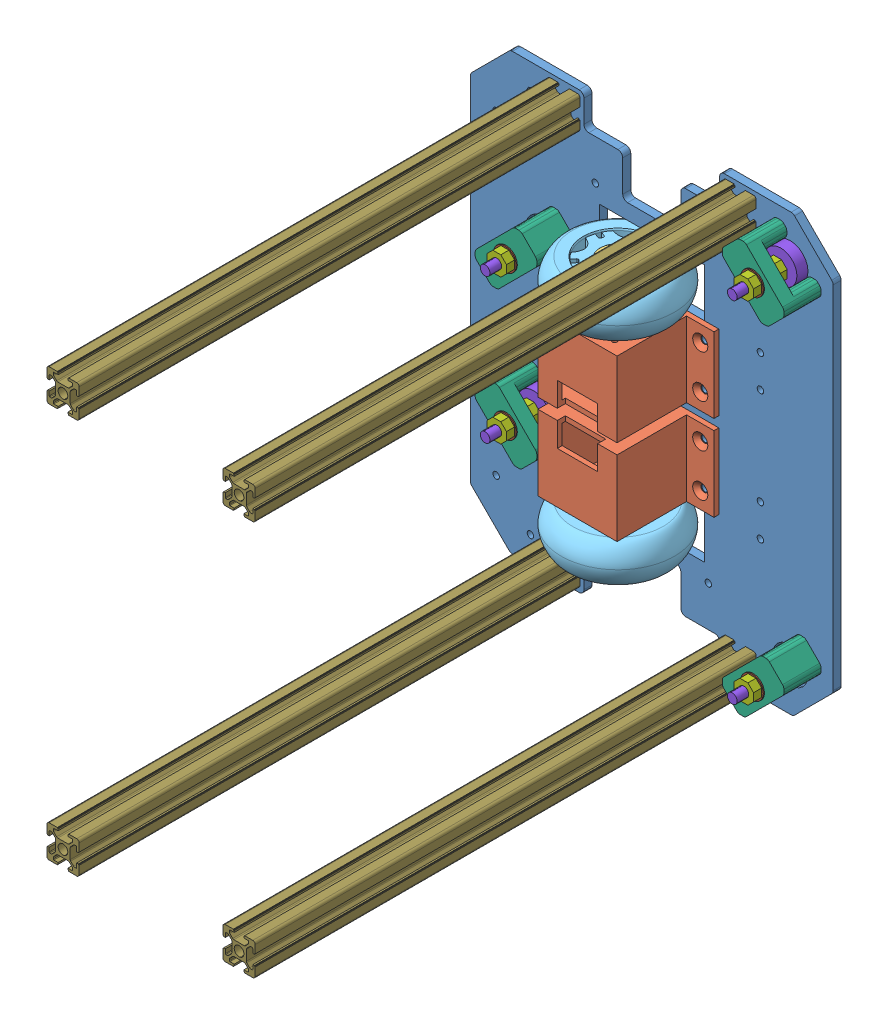
SolidWorks assembly base roulante, configuration Défaut. Lengths in mm.
Overall size (224.5 269.5 367.12).
63 component instances, 12 part files, 32 mates.
Components (placement in the parent):
- plaque base roulante 2-1: plaque base roulante 2 [Défaut] at (315.8571 -54.1365 122.0217) size (224.5 269.5 5)
- support-1: support [Défaut] at (206.8571 77.3635 170.0217) x (-1 0 0) z (0 -1 0) size (83 46 46.5)
- support-2: support [Défaut] at (249.8571 83.861 170.0217) x (1 0 0) z (0 1 0) size (83 46 46.5)
- Assemblage 5mm-1: Assemblage 5mm [Défaut] at (210.2333 168.7277 150.2073) x (0.837948 0 -0.54575) z (0 -1 0) size (70.03 70.03 25.12)
  - moyeu pololu (axe 5mm) part 2-1: moyeu pololu (axe 5mm) part 2 [Défaut] at (16.3796 8.0597 10.6516) size (21.9 21.9 3)
  - moyeux pololu (axe 5mm)-1: moyeux pololu (axe 5mm) [Défaut] at (16.3796 8.0597 27.1516) x (0.866025 0.5 0) z (0 0 1) size (22 22 12)
  - Roue Scooter noire 70x25 mm 3272-1: Roue Scooter noire 70x25 mm 3272 [Défaut] at (16.3796 8.0597 22.1516) size (70.03 70.03 25.12)
- Assemblage 5mm-2: Assemblage 5mm [Défaut] at (224.692 -6.3904 165.9052) x (0.612655 0 -0.79035) z (0 1 0) size (70.03 70.03 25.12)
  - moyeu pololu (axe 5mm) part 2-1: moyeu pololu (axe 5mm) part 2 [Défaut] at (16.3796 8.0597 10.6516) size (21.9 21.9 3)
  - moyeux pololu (axe 5mm)-1: moyeux pololu (axe 5mm) [Défaut] at (16.3796 8.0597 27.1516) x (0.866025 0.5 0) z (0 0 1) size (22 22 12)
  - Roue Scooter noire 70x25 mm 3272-1: Roue Scooter noire 70x25 mm 3272 [Défaut] at (16.3796 8.0597 22.1516) size (70.03 70.03 25.12)
- Assemblage Roue Porteuse-1: Assemblage Roue Porteuse [Défaut] at (293.5978 171.1781 157.1111) x (0.707107 -0.707107 0) z (-0.707107 -0.707107 0) size (40 50.71 20)
  - Support Bille porteuse-1: Support Bille porteuse [Défaut] at (1.9744 -30.0894 -26.9817) size (40 23 20)
  - Ecrou M6-3: Ecrou M6 [Défaut] at (1.9744 -17.1894 -26.9817) x (1 0 0) z (0 -1 0) size (12 12 5)
  - Ecrou M6-2: Ecrou M6 [Défaut] at (1.9744 -1.3894 -26.9817) x (1 0 0) z (0 -1 0) size (12 12 5)
  - Bille porteuse ALWAYE D12_7-2: Bille porteuse ALWAYE D12_7 [Défaut] at (1.9744 -30.1894 -26.9817) size (20 46.5 20)
  - Bille D12-2: Bille D12 [Défaut] at (1.9744 -38.8998 -26.9817) size (12 12 12)
  - Insert M4-2: Insert M4 [Défaut] at (16.9744 -30.0894 -26.9817) x (-0.837169 0 -0.546944) z (0 1 0) size (7 7 8)
  - Insert M4-3: Insert M4 [Défaut] at (-13.0256 -30.0894 -26.9817) x (-0.837169 0 -0.546944) z (0 1 0) size (7 7 8)
  - Rondelle M6-6: Rondelle M6 [Défaut] at (1.9744 -17.1894 -26.9817) x (1 0 0) z (0 1 0) size (14 14 0.7)
  - Rondelle M6-7: Rondelle M6 [Défaut] at (1.9744 -16.4894 -26.9817) x (1 0 0) z (0 1 0) size (14 14 0.7)
  - Rondelle M6-5: Rondelle M6 [Défaut] at (1.9744 -15.7894 -26.9817) x (1 0 0) z (0 1 0) size (14 14 0.7)
  - Rondelle M6-4: Rondelle M6 [Défaut] at (1.9744 -7.0894 -26.9817) x (1 0 0) z (0 1 0) size (14 14 0.7)
- Assemblage Roue Porteuse-2: Assemblage Roue Porteuse [Défaut] at (331.7557 -48.1115 157.1111) x (0.707107 0.707107 0) z (0.707107 -0.707107 0) size (40 50.71 20)
  - Support Bille porteuse-1: Support Bille porteuse [Défaut] at (1.9744 -30.0894 -26.9817) size (40 23 20)
  - Ecrou M6-3: Ecrou M6 [Défaut] at (1.9744 -17.1894 -26.9817) x (1 0 0) z (0 -1 0) size (12 12 5)
  - Ecrou M6-2: Ecrou M6 [Défaut] at (1.9744 -1.3894 -26.9817) x (1 0 0) z (0 -1 0) size (12 12 5)
  - Bille porteuse ALWAYE D12_7-2: Bille porteuse ALWAYE D12_7 [Défaut] at (1.9744 -30.1894 -26.9817) size (20 46.5 20)
  - Bille D12-2: Bille D12 [Défaut] at (1.9744 -38.8998 -26.9817) size (12 12 12)
  - Insert M4-2: Insert M4 [Défaut] at (16.9744 -30.0894 -26.9817) x (-0.837169 0 -0.546944) z (0 1 0) size (7 7 8)
  - Insert M4-3: Insert M4 [Défaut] at (-13.0256 -30.0894 -26.9817) x (-0.837169 0 -0.546944) z (0 1 0) size (7 7 8)
  - Rondelle M6-6: Rondelle M6 [Défaut] at (1.9744 -17.1894 -26.9817) x (1 0 0) z (0 1 0) size (14 14 0.7)
  - Rondelle M6-7: Rondelle M6 [Défaut] at (1.9744 -16.4894 -26.9817) x (1 0 0) z (0 1 0) size (14 14 0.7)
  - Rondelle M6-5: Rondelle M6 [Défaut] at (1.9744 -15.7894 -26.9817) x (1 0 0) z (0 1 0) size (14 14 0.7)
  - Rondelle M6-4: Rondelle M6 [Défaut] at (1.9744 -7.0894 -26.9817) x (1 0 0) z (0 1 0) size (14 14 0.7)
- Assemblage Roue Porteuse-3: Assemblage Roue Porteuse [Défaut] at (178.7912 104.8859 157.1111) x (0.707107 0.707107 0) z (0.707107 -0.707107 0) size (40 50.71 20)
  - Support Bille porteuse-1: Support Bille porteuse [Défaut] at (1.9744 -30.0894 -26.9817) size (40 23 20)
  - Ecrou M6-3: Ecrou M6 [Défaut] at (1.9744 -17.1894 -26.9817) x (1 0 0) z (0 -1 0) size (12 12 5)
  - Ecrou M6-2: Ecrou M6 [Défaut] at (1.9744 -1.3894 -26.9817) x (1 0 0) z (0 -1 0) size (12 12 5)
  - Bille porteuse ALWAYE D12_7-2: Bille porteuse ALWAYE D12_7 [Défaut] at (1.9744 -30.1894 -26.9817) size (20 46.5 20)
  - Bille D12-2: Bille D12 [Défaut] at (1.9744 -38.8998 -26.9817) size (12 12 12)
  - Insert M4-2: Insert M4 [Défaut] at (16.9744 -30.0894 -26.9817) x (-0.837169 0 -0.546944) z (0 1 0) size (7 7 8)
  - Insert M4-3: Insert M4 [Défaut] at (-13.0256 -30.0894 -26.9817) x (-0.837169 0 -0.546944) z (0 1 0) size (7 7 8)
  - Rondelle M6-6: Rondelle M6 [Défaut] at (1.9744 -17.1894 -26.9817) x (1 0 0) z (0 1 0) size (14 14 0.7)
  - Rondelle M6-7: Rondelle M6 [Défaut] at (1.9744 -16.4894 -26.9817) x (1 0 0) z (0 1 0) size (14 14 0.7)
  - Rondelle M6-5: Rondelle M6 [Défaut] at (1.9744 -15.7894 -26.9817) x (1 0 0) z (0 1 0) size (14 14 0.7)
  - Rondelle M6-4: Rondelle M6 [Défaut] at (1.9744 -7.0894 -26.9817) x (1 0 0) z (0 1 0) size (14 14 0.7)
- Assemblage Roue Porteuse-4: Assemblage Roue Porteuse [Défaut] at (181.5834 53.5463 157.1111) x (-0.707107 0.707107 0) z (0.707107 0.707107 0) size (40 50.71 20)
  - Support Bille porteuse-1: Support Bille porteuse [Défaut] at (1.9744 -30.0894 -26.9817) size (40 23 20)
  - Ecrou M6-3: Ecrou M6 [Défaut] at (1.9744 -17.1894 -26.9817) x (1 0 0) z (0 -1 0) size (12 12 5)
  - Ecrou M6-2: Ecrou M6 [Défaut] at (1.9744 -1.3894 -26.9817) x (1 0 0) z (0 -1 0) size (12 12 5)
  - Bille porteuse ALWAYE D12_7-2: Bille porteuse ALWAYE D12_7 [Défaut] at (1.9744 -30.1894 -26.9817) size (20 46.5 20)
  - Bille D12-2: Bille D12 [Défaut] at (1.9744 -38.8998 -26.9817) size (12 12 12)
  - Insert M4-2: Insert M4 [Défaut] at (16.9744 -30.0894 -26.9817) x (-0.837169 0 -0.546944) z (0 1 0) size (7 7 8)
  - Insert M4-3: Insert M4 [Défaut] at (-13.0256 -30.0894 -26.9817) x (-0.837169 0 -0.546944) z (0 1 0) size (7 7 8)
  - Rondelle M6-6: Rondelle M6 [Défaut] at (1.9744 -17.1894 -26.9817) x (1 0 0) z (0 1 0) size (14 14 0.7)
  - Rondelle M6-7: Rondelle M6 [Défaut] at (1.9744 -16.4894 -26.9817) x (1 0 0) z (0 1 0) size (14 14 0.7)
  - Rondelle M6-5: Rondelle M6 [Défaut] at (1.9744 -15.7894 -26.9817) x (1 0 0) z (0 1 0) size (14 14 0.7)
  - Rondelle M6-4: Rondelle M6 [Défaut] at (1.9744 -7.0894 -26.9817) x (1 0 0) z (0 1 0) size (14 14 0.7)
- Profilé Aluminium Bosch Rexroth 20 x 20 mm-1: Profilé Aluminium Bosch Rexroth 20 x 20 mm [Défaut] at (173.8571 202.861 127.0217) x (1 0 0) z (0 -1 0) size (20 339 20)
- Profilé Aluminium Bosch Rexroth 20 x 20 mm-2: Profilé Aluminium Bosch Rexroth 20 x 20 mm [Défaut] at (282.8571 -41.6365 127.0217) x (1 0 0) z (0 -1 0) size (20 339 20)
- Profilé Aluminium Bosch Rexroth 20 x 20 mm-3: Profilé Aluminium Bosch Rexroth 20 x 20 mm [Défaut] at (173.8571 -41.6365 127.0217) x (1 0 0) z (0 -1 0) size (20 339 20)
- Profilé Aluminium Bosch Rexroth 20 x 20 mm-4: Profilé Aluminium Bosch Rexroth 20 x 20 mm [Défaut] at (282.8571 202.861 127.0217) x (1 0 0) z (0 -1 0) size (20 339 20)
Mates (geometry in assembly coordinates):
- Coïncidente1: coincident anti-aligned: plane of plaque base roulante 2-1 through (315.8571 -54.1365 127.0217) normal (0 0 1); plane of support-1 through (249.8571 30.8635 127.0217) normal (0 0 -1)
- Coïncidente2: coincident anti-aligned: plane of plaque base roulante 2-1 through (315.8571 -54.1365 127.0217) normal (0 0 1); plane of support-2 through (206.8571 130.361 127.0217) normal (0 0 -1)
- Coïncidente3: coincident aligned: plane of plaque base roulante 2-1 through (260.8571 130.361 127.0217) normal (0 1 0); plane of support-2 through (249.8571 130.361 170.0217) normal (0 1 0)
- Coaxiale1: concentric aligned: cylinder of plaque base roulante 2-1 through (195.3571 120.361 122.0217) axis (0 0 1) radius 2; circle of support-2
- Parallèle1: parallel anti-aligned: plane of support-1 through (206.8571 77.3635 170.0217) normal (0 1 0); plane of support-2 through (249.8571 83.861 170.0217) normal (0 -1 0)
- Coaxiale2: concentric aligned: circle of plaque base roulante 2-1; circle of support-1
- Coaxiale3: concentric aligned: cylinder of plaque base roulante 2-1 through (261.3571 67.3635 122.0217) axis (0 0 1) radius 2; circle of support-1
- Coaxiale4: concentric anti-aligned: circle of support-1; circle of Assemblage 5mm-2/moyeux pololu (axe 5mm)-1
- Coaxiale5: concentric anti-aligned: circle of support-2; cylinder of Assemblage 5mm-1/moyeux pololu (axe 5mm)-1 through (228.3571 147.0761 148.0217) axis (0 -1 0) radius 2.51
- Coïncidente7: coincident anti-aligned: plane of plaque base roulante 2-1 through (315.8571 -54.1365 127.0217) normal (0 0 1); plane of Assemblage Roue Porteuse-1/Support Bille porteuse-1 through (314.0729 188.861 127.0217) normal (0 0 -1)
- Coaxiale6: concentric anti-aligned: cylinder of plaque base roulante 2-1 through (314.0729 188.861 122.0207) axis (0 0 1) radius 11; cylinder of Assemblage Roue Porteuse-1/Bille porteuse ALWAYE D12_7-2 through (314.0729 188.861 130.9217) axis (0 0 -1) radius 10
- Coaxiale7: concentric anti-aligned: circle of plaque base roulante 2-1; cylinder of Assemblage Roue Porteuse-1/Insert M4-2 through (324.6795 178.2544 135.0217) axis (0 0 -1) radius 2
- Coaxiale8: concentric anti-aligned: cylinder of plaque base roulante 2-1 through (314.0729 -27.6365 122.0207) axis (0 0 1) radius 11; cylinder of Assemblage Roue Porteuse-2/Bille porteuse ALWAYE D12_7-2 through (314.0729 -27.6365 130.9217) axis (0 0 -1) radius 10
- Coïncidente9: coincident anti-aligned: plane of plaque base roulante 2-1 through (315.8571 -54.1365 127.0217) normal (0 0 1); plane of Assemblage Roue Porteuse-2/Support Bille porteuse-1 through (314.0729 -27.6365 127.0217) normal (0 0 -1)
- Coaxiale9: concentric anti-aligned: cylinder of plaque base roulante 2-1 through (324.6795 -17.0299 122.0207) axis (0 0 1) radius 2; cylinder of Assemblage Roue Porteuse-2/Insert M4-2 through (324.6795 -17.0299 135.0217) axis (0 0 -1) radius 2
- Coaxiale10: concentric anti-aligned: cylinder of plaque base roulante 2-1 through (161.1084 35.8635 122.0207) axis (0 0 1) radius 11; cylinder of Assemblage Roue Porteuse-4/Bille porteuse ALWAYE D12_7-2 through (161.1084 35.8635 130.9217) axis (0 0 -1) radius 10
- Coïncidente10: coincident anti-aligned: plane of plaque base roulante 2-1 through (315.8571 -54.1365 127.0217) normal (0 0 1); plane of Assemblage Roue Porteuse-4/Support Bille porteuse-1 through (161.1084 35.8635 127.0217) normal (0 0 -1)
- Coaxiale11: concentric anti-aligned: cylinder of plaque base roulante 2-1 through (171.715 25.2569 122.0207) axis (0 0 1) radius 2; cylinder of Assemblage Roue Porteuse-4/Insert M4-3 through (171.715 25.2569 135.0217) axis (0 0 -1) radius 2
- Coaxiale13: concentric anti-aligned: circle of plaque base roulante 2-1; cylinder of Assemblage Roue Porteuse-3/Bille porteuse ALWAYE D12_7-2 through (161.1084 125.361 130.9217) axis (0 0 -1) radius 10
- Coïncidente12: coincident aligned: circle of plaque base roulante 2-1; circle of Assemblage Roue Porteuse-3/Insert M4-3
- Coïncidente13: coincident anti-aligned: plane of plaque base roulante 2-1 through (315.8571 -54.1365 127.0217) normal (0 0 1); plane of Profilé Aluminium Bosch Rexroth 20 x 20 mm-3 through (173.8571 -41.6365 127.0217) normal (0 0 -1)
- Coïncidente14: coincident anti-aligned: plane of plaque base roulante 2-1 through (315.8571 -54.1365 127.0217) normal (0 0 1); plane of Profilé Aluminium Bosch Rexroth 20 x 20 mm-2 through (282.8571 -41.6365 127.0217) normal (0 0 -1)
- Coïncidente15: coincident anti-aligned: plane of plaque base roulante 2-1 through (315.8571 -54.1365 127.0217) normal (0 0 1); plane of Profilé Aluminium Bosch Rexroth 20 x 20 mm-4 through (282.8571 202.861 127.0217) normal (0 0 -1)
- Coïncidente16: coincident anti-aligned: plane of plaque base roulante 2-1 through (315.8571 -54.1365 127.0217) normal (0 0 1); plane of Profilé Aluminium Bosch Rexroth 20 x 20 mm-1 through (173.8571 202.861 127.0217) normal (0 0 -1)
- Coaxiale14: concentric anti-aligned: cylinder of plaque base roulante 2-1 through (173.8571 -41.6365 122.0207) axis (0 0 1) radius 3; cylinder of Profilé Aluminium Bosch Rexroth 20 x 20 mm-3 through (173.8571 -41.6365 466.0217) axis (0 0 -1) radius 3
- Coaxiale15: concentric anti-aligned: cylinder of plaque base roulante 2-1 through (282.8571 -41.6365 122.0207) axis (0 0 1) radius 3; cylinder of Profilé Aluminium Bosch Rexroth 20 x 20 mm-2 through (282.8571 -41.6365 466.0217) axis (0 0 -1) radius 3
- Coïncidente17: coincident anti-aligned: cylinder of plaque base roulante 2-1 through (282.8571 202.861 122.0207) axis (0 0 1) radius 3; circle of Profilé Aluminium Bosch Rexroth 20 x 20 mm-4
- Coïncidente18: coincident anti-aligned: circle of plaque base roulante 2-1; cylinder of Profilé Aluminium Bosch Rexroth 20 x 20 mm-1 through (173.8571 202.861 466.0217) axis (0 0 -1) radius 3
- Parallèle2: parallel aligned: plane of plaque base roulante 2-1 through (140.8571 215.361 127.0217) normal (0 1 0); plane of Profilé Aluminium Bosch Rexroth 20 x 20 mm-1 through (163.8571 212.861 466.0217) normal (0 1 0)
- Parallèle3: parallel aligned: plane of plaque base roulante 2-1 through (140.8571 215.361 127.0217) normal (0 1 0); plane of Profilé Aluminium Bosch Rexroth 20 x 20 mm-4 through (272.8571 212.861 466.0217) normal (0 1 0)
- Parallèle4: parallel aligned: plane of plaque base roulante 2-1 through (315.8571 -54.1365 127.0217) normal (0 -1 0); plane of Profilé Aluminium Bosch Rexroth 20 x 20 mm-3 through (183.8571 -51.6365 466.0217) normal (0 -1 0)
- Parallèle5: parallel: line of plaque base roulante 2-1 through (273.3571 -54.1365 122.0217) axis (1 0 0); plane of Profilé Aluminium Bosch Rexroth 20 x 20 mm-2 through (272.8571 -51.6365 466.0217) normal (0 -1 0)
